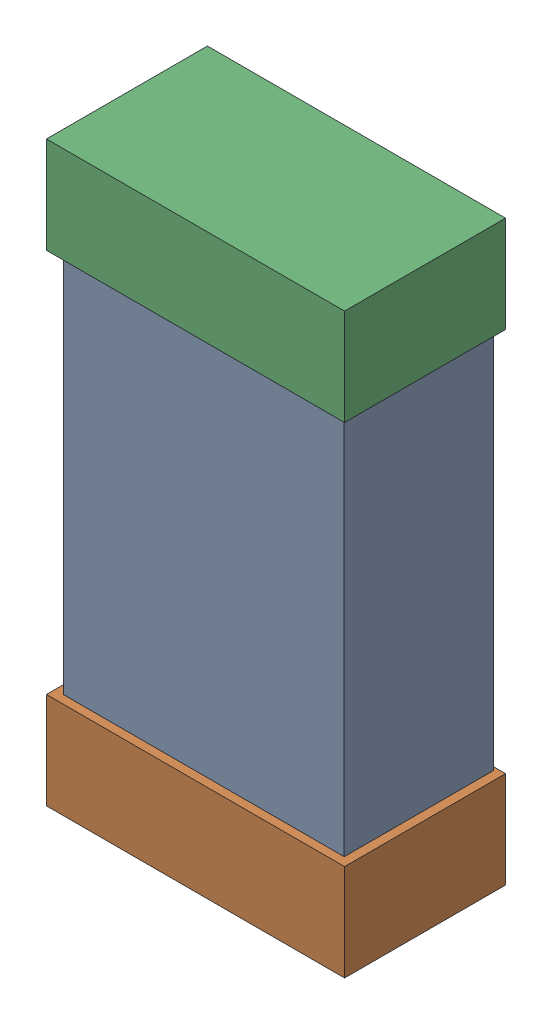
SolidWorks assembly C27, configuration Default. Lengths in mm.
Overall size (0.85 1.65 0.46).
6 component instances, 2 part files, 0 mates.
Components (placement in the parent):
- 432124816_37-1: 432124816_37 [Default] at (23.1251 19.4533 -0.8615) size (0.8 1.5 0.42)
  - Extruded (1)-1: Extruded (1) [Default] at origin size (0.8 1.5 0.42)
- 432138512_74-1: 432138512_74 [Default] at (23.1251 18.7675 -0.8715) size (0.85 0.28 0.46)
  - Extruded-1: Extruded [Default] at origin size (0.85 0.28 0.46)
- 432138512_75-1: 432138512_75 [Default] at (23.1251 20.1391 -0.8715) size (0.85 0.28 0.46)
  - Extruded-1: Extruded [Default] at origin size (0.85 0.28 0.46)
